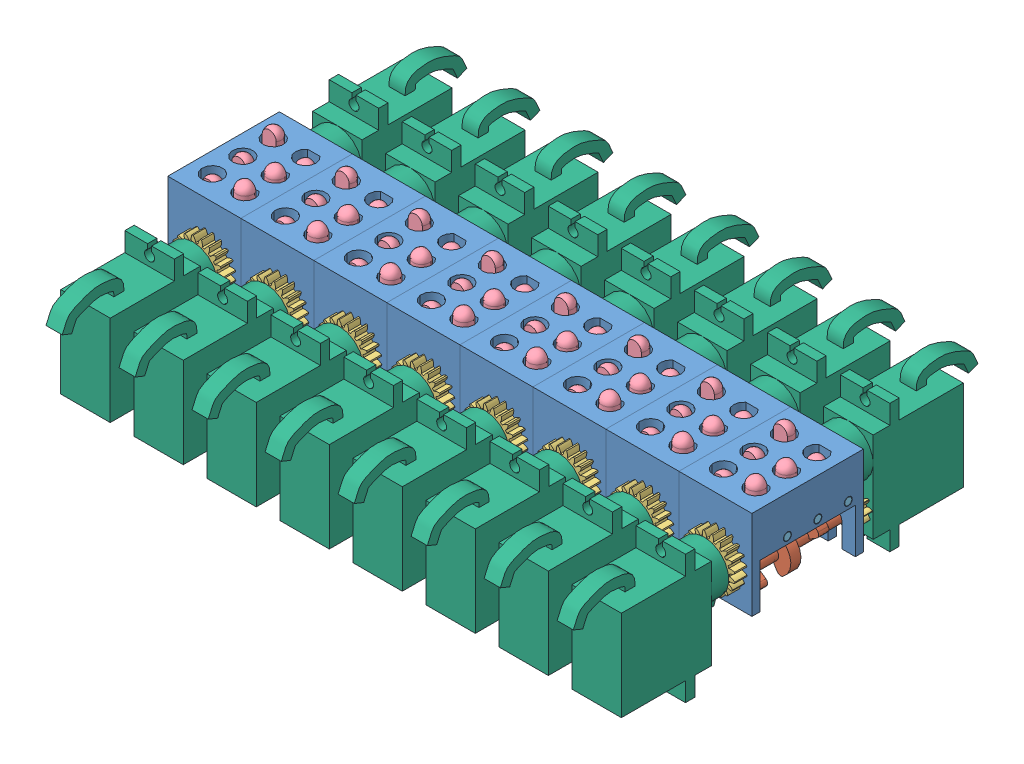
SolidWorks assembly Сборка1, configuration По умолчанию. Lengths in mm.
Overall size (146.18 34.4 106.77).
192 component instances, 6 part files, 21 mates.
Components (placement in the parent):
- cell-1: cell [По умолчанию] at origin size (20.18 34.4 106.77)
  - housing-1: housing [По умолчанию] at origin size (18 22 27.5)
  - rotor-1: rotor [По умолчанию] at (4 -16 -17.35) x (0.358478 -0.933538 0) z (0 0 1) size (9 8.9 33.5)
    - rotor-1: rotor [По умолчанию] at origin size (9 8.9 33.5)
    - spur gear_am-1: spur gear_am [Metric - Spur gear 0.6M 10T 20PA 3FW ---S10N75H50L3N] at (0 0 3) x (0 0 -1) z (1 0 0) size (3 6.89 7.2)
  - pin-2: pin [По умолчанию] at (4 -9.7016 -0.75) x (-1 0 0) z (0 0 -1) size (4 14 4.5)
  - pin-3: pin [По умолчанию] at (4 -12.4261 -8.25) x (-1 0 0) z (0 0 -1) size (4 14 4.5)
  - separator-1: separator [По умолчанию] at (0 -9.3 5) size (9 1.75 1.75)
  - separator-2: separator [По умолчанию] at (0 -9.3 -2.5) size (9 1.75 1.75)
  - rotor-3: rotor [По умолчанию] at (-4 -16 18.952) x (0.331867 0.943326 0) z (0 0 -1) size (9 8.9 33.5)
    - rotor-1: rotor [По умолчанию] at origin size (9 8.9 33.5)
    - spur gear_am-1: spur gear_am [Metric - Spur gear 0.6M 10T 20PA 3FW ---S10N75H50L3N] at (0 0 3) x (0 0 -1) z (1 0 0) size (3 6.89 7.2)
  - pin-4: pin [По умолчанию] at (4 -9.3768 6.75) x (-1 0 0) z (0 0 -1) size (4 14 4.5)
  - separator-3: separator [По умолчанию] at (0 -9.3 -10) size (9 1.75 1.75)
  - servo-1: servo [По умолчанию] at (-3.6042 -4.7 -44.85) x (-1 0 0) z (0 1 0) size (12.2 36.83 31.7)
  - servo-2: servo [По умолчанию] at (3.4181 -4.7 46.452) x (1 0 0) z (0 1 0) size (12.2 36.83 31.7)
  - spur gear_am-1: spur gear_am [Metric - Spur gear 0.6M 20T 20PA 3FW ---S20N75H50L5N] at (3.4181 -10.8 15.952) x (0 0 1) z (-0.999929 -0.011884 0) size (3 13.08 13.08)
  - spur gear_am-2: spur gear_am [Metric - Spur gear 0.6M 20T 20PA 3FW ---S20N75H50L5N] at (-3.6042 -10.8 -14.35) x (0 0 -1) z (1 0 0) size (3 13.08 13.08)
  - separator-4: separator [По умолчанию] at (-9 -9.3 -5) size (9 1.75 1.75)
  - separator-5: separator [По умолчанию] at (-9 -9.3 2.5) size (9 1.75 1.75)
  - separator-6: separator [По умолчанию] at (-9 -9.3 10) size (9 1.75 1.75)
  - pin-5: pin [По умолчанию] at (-4 -9.2986 -6.25) size (4 14 4.5)
  - pin-6: pin [По умолчанию] at (-4 -11.4111 1.25) size (4 14 4.5)
  - pin-7: pin [По умолчанию] at (-4 -12.4437 8.75) size (4 14 4.5)
- cell-2: cell [По умолчанию] at (18 0 0) size (20.18 34.4 106.77)
  - housing-1: housing [По умолчанию] at origin size (18 22 27.5)
  - rotor-1: rotor [По умолчанию] at (4 -16 -17.35) x (0.358478 -0.933538 0) z (0 0 1) size (9 8.9 33.5)
    - rotor-1: rotor [По умолчанию] at origin size (9 8.9 33.5)
    - spur gear_am-1: spur gear_am [Metric - Spur gear 0.6M 10T 20PA 3FW ---S10N75H50L3N] at (0 0 3) x (0 0 -1) z (1 0 0) size (3 6.89 7.2)
  - pin-2: pin [По умолчанию] at (4 -9.7016 -0.75) x (-1 0 0) z (0 0 -1) size (4 14 4.5)
  - pin-3: pin [По умолчанию] at (4 -12.4261 -8.25) x (-1 0 0) z (0 0 -1) size (4 14 4.5)
  - separator-1: separator [По умолчанию] at (0 -9.3 5) size (9 1.75 1.75)
  - separator-2: separator [По умолчанию] at (0 -9.3 -2.5) size (9 1.75 1.75)
  - rotor-3: rotor [По умолчанию] at (-4 -16 18.952) x (0.331867 0.943326 0) z (0 0 -1) size (9 8.9 33.5)
    - rotor-1: rotor [По умолчанию] at origin size (9 8.9 33.5)
    - spur gear_am-1: spur gear_am [Metric - Spur gear 0.6M 10T 20PA 3FW ---S10N75H50L3N] at (0 0 3) x (0 0 -1) z (1 0 0) size (3 6.89 7.2)
  - pin-4: pin [По умолчанию] at (4 -9.3768 6.75) x (-1 0 0) z (0 0 -1) size (4 14 4.5)
  - separator-3: separator [По умолчанию] at (0 -9.3 -10) size (9 1.75 1.75)
  - servo-1: servo [По умолчанию] at (-3.6042 -4.7 -44.85) x (-1 0 0) z (0 1 0) size (12.2 36.83 31.7)
  - servo-2: servo [По умолчанию] at (3.4181 -4.7 46.452) x (1 0 0) z (0 1 0) size (12.2 36.83 31.7)
  - spur gear_am-1: spur gear_am [Metric - Spur gear 0.6M 20T 20PA 3FW ---S20N75H50L5N] at (3.4181 -10.8 15.952) x (0 0 1) z (-0.999929 -0.011884 0) size (3 13.08 13.08)
  - spur gear_am-2: spur gear_am [Metric - Spur gear 0.6M 20T 20PA 3FW ---S20N75H50L5N] at (-3.6042 -10.8 -14.35) x (0 0 -1) z (1 0 0) size (3 13.08 13.08)
  - separator-4: separator [По умолчанию] at (-9 -9.3 -5) size (9 1.75 1.75)
  - separator-5: separator [По умолчанию] at (-9 -9.3 2.5) size (9 1.75 1.75)
  - separator-6: separator [По умолчанию] at (-9 -9.3 10) size (9 1.75 1.75)
  - pin-5: pin [По умолчанию] at (-4 -9.2986 -6.25) size (4 14 4.5)
  - pin-6: pin [По умолчанию] at (-4 -11.4111 1.25) size (4 14 4.5)
  - pin-7: pin [По умолчанию] at (-4 -12.4437 8.75) size (4 14 4.5)
- cell-3: cell [По умолчанию] at (36 0 0) size (20.18 34.4 106.77)
  - housing-1: housing [По умолчанию] at origin size (18 22 27.5)
  - rotor-1: rotor [По умолчанию] at (4 -16 -17.35) x (0.358478 -0.933538 0) z (0 0 1) size (9 8.9 33.5)
    - rotor-1: rotor [По умолчанию] at origin size (9 8.9 33.5)
    - spur gear_am-1: spur gear_am [Metric - Spur gear 0.6M 10T 20PA 3FW ---S10N75H50L3N] at (0 0 3) x (0 0 -1) z (1 0 0) size (3 6.89 7.2)
  - pin-2: pin [По умолчанию] at (4 -9.7016 -0.75) x (-1 0 0) z (0 0 -1) size (4 14 4.5)
  - pin-3: pin [По умолчанию] at (4 -12.4261 -8.25) x (-1 0 0) z (0 0 -1) size (4 14 4.5)
  - separator-1: separator [По умолчанию] at (0 -9.3 5) size (9 1.75 1.75)
  - separator-2: separator [По умолчанию] at (0 -9.3 -2.5) size (9 1.75 1.75)
  - rotor-3: rotor [По умолчанию] at (-4 -16 18.952) x (0.331867 0.943326 0) z (0 0 -1) size (9 8.9 33.5)
    - rotor-1: rotor [По умолчанию] at origin size (9 8.9 33.5)
    - spur gear_am-1: spur gear_am [Metric - Spur gear 0.6M 10T 20PA 3FW ---S10N75H50L3N] at (0 0 3) x (0 0 -1) z (1 0 0) size (3 6.89 7.2)
  - pin-4: pin [По умолчанию] at (4 -9.3768 6.75) x (-1 0 0) z (0 0 -1) size (4 14 4.5)
  - separator-3: separator [По умолчанию] at (0 -9.3 -10) size (9 1.75 1.75)
  - servo-1: servo [По умолчанию] at (-3.6042 -4.7 -44.85) x (-1 0 0) z (0 1 0) size (12.2 36.83 31.7)
  - servo-2: servo [По умолчанию] at (3.4181 -4.7 46.452) x (1 0 0) z (0 1 0) size (12.2 36.83 31.7)
  - spur gear_am-1: spur gear_am [Metric - Spur gear 0.6M 20T 20PA 3FW ---S20N75H50L5N] at (3.4181 -10.8 15.952) x (0 0 1) z (-0.999929 -0.011884 0) size (3 13.08 13.08)
  - spur gear_am-2: spur gear_am [Metric - Spur gear 0.6M 20T 20PA 3FW ---S20N75H50L5N] at (-3.6042 -10.8 -14.35) x (0 0 -1) z (1 0 0) size (3 13.08 13.08)
  - separator-4: separator [По умолчанию] at (-9 -9.3 -5) size (9 1.75 1.75)
  - separator-5: separator [По умолчанию] at (-9 -9.3 2.5) size (9 1.75 1.75)
  - separator-6: separator [По умолчанию] at (-9 -9.3 10) size (9 1.75 1.75)
  - pin-5: pin [По умолчанию] at (-4 -9.2986 -6.25) size (4 14 4.5)
  - pin-6: pin [По умолчанию] at (-4 -11.4111 1.25) size (4 14 4.5)
  - pin-7: pin [По умолчанию] at (-4 -12.4437 8.75) size (4 14 4.5)
- cell-4: cell [По умолчанию] at (54 0 0) size (20.18 34.4 106.77)
  - housing-1: housing [По умолчанию] at origin size (18 22 27.5)
  - rotor-1: rotor [По умолчанию] at (4 -16 -17.35) x (0.358478 -0.933538 0) z (0 0 1) size (9 8.9 33.5)
    - rotor-1: rotor [По умолчанию] at origin size (9 8.9 33.5)
    - spur gear_am-1: spur gear_am [Metric - Spur gear 0.6M 10T 20PA 3FW ---S10N75H50L3N] at (0 0 3) x (0 0 -1) z (1 0 0) size (3 6.89 7.2)
  - pin-2: pin [По умолчанию] at (4 -9.7016 -0.75) x (-1 0 0) z (0 0 -1) size (4 14 4.5)
  - pin-3: pin [По умолчанию] at (4 -12.4261 -8.25) x (-1 0 0) z (0 0 -1) size (4 14 4.5)
  - separator-1: separator [По умолчанию] at (0 -9.3 5) size (9 1.75 1.75)
  - separator-2: separator [По умолчанию] at (0 -9.3 -2.5) size (9 1.75 1.75)
  - rotor-3: rotor [По умолчанию] at (-4 -16 18.952) x (0.331867 0.943326 0) z (0 0 -1) size (9 8.9 33.5)
    - rotor-1: rotor [По умолчанию] at origin size (9 8.9 33.5)
    - spur gear_am-1: spur gear_am [Metric - Spur gear 0.6M 10T 20PA 3FW ---S10N75H50L3N] at (0 0 3) x (0 0 -1) z (1 0 0) size (3 6.89 7.2)
  - pin-4: pin [По умолчанию] at (4 -9.3768 6.75) x (-1 0 0) z (0 0 -1) size (4 14 4.5)
  - separator-3: separator [По умолчанию] at (0 -9.3 -10) size (9 1.75 1.75)
  - servo-1: servo [По умолчанию] at (-3.6042 -4.7 -44.85) x (-1 0 0) z (0 1 0) size (12.2 36.83 31.7)
  - servo-2: servo [По умолчанию] at (3.4181 -4.7 46.452) x (1 0 0) z (0 1 0) size (12.2 36.83 31.7)
  - spur gear_am-1: spur gear_am [Metric - Spur gear 0.6M 20T 20PA 3FW ---S20N75H50L5N] at (3.4181 -10.8 15.952) x (0 0 1) z (-0.999929 -0.011884 0) size (3 13.08 13.08)
  - spur gear_am-2: spur gear_am [Metric - Spur gear 0.6M 20T 20PA 3FW ---S20N75H50L5N] at (-3.6042 -10.8 -14.35) x (0 0 -1) z (1 0 0) size (3 13.08 13.08)
  - separator-4: separator [По умолчанию] at (-9 -9.3 -5) size (9 1.75 1.75)
  - separator-5: separator [По умолчанию] at (-9 -9.3 2.5) size (9 1.75 1.75)
  - separator-6: separator [По умолчанию] at (-9 -9.3 10) size (9 1.75 1.75)
  - pin-5: pin [По умолчанию] at (-4 -9.2986 -6.25) size (4 14 4.5)
  - pin-6: pin [По умолчанию] at (-4 -11.4111 1.25) size (4 14 4.5)
  - pin-7: pin [По умолчанию] at (-4 -12.4437 8.75) size (4 14 4.5)
- cell-5: cell [По умолчанию] at (72 0 0) size (20.18 34.4 106.77)
  - housing-1: housing [По умолчанию] at origin size (18 22 27.5)
  - rotor-1: rotor [По умолчанию] at (4 -16 -17.35) x (0.358478 -0.933538 0) z (0 0 1) size (9 8.9 33.5)
    - rotor-1: rotor [По умолчанию] at origin size (9 8.9 33.5)
    - spur gear_am-1: spur gear_am [Metric - Spur gear 0.6M 10T 20PA 3FW ---S10N75H50L3N] at (0 0 3) x (0 0 -1) z (1 0 0) size (3 6.89 7.2)
  - pin-2: pin [По умолчанию] at (4 -9.7016 -0.75) x (-1 0 0) z (0 0 -1) size (4 14 4.5)
  - pin-3: pin [По умолчанию] at (4 -12.4261 -8.25) x (-1 0 0) z (0 0 -1) size (4 14 4.5)
  - separator-1: separator [По умолчанию] at (0 -9.3 5) size (9 1.75 1.75)
  - separator-2: separator [По умолчанию] at (0 -9.3 -2.5) size (9 1.75 1.75)
  - rotor-3: rotor [По умолчанию] at (-4 -16 18.952) x (0.331867 0.943326 0) z (0 0 -1) size (9 8.9 33.5)
    - rotor-1: rotor [По умолчанию] at origin size (9 8.9 33.5)
    - spur gear_am-1: spur gear_am [Metric - Spur gear 0.6M 10T 20PA 3FW ---S10N75H50L3N] at (0 0 3) x (0 0 -1) z (1 0 0) size (3 6.89 7.2)
  - pin-4: pin [По умолчанию] at (4 -9.3768 6.75) x (-1 0 0) z (0 0 -1) size (4 14 4.5)
  - separator-3: separator [По умолчанию] at (0 -9.3 -10) size (9 1.75 1.75)
  - servo-1: servo [По умолчанию] at (-3.6042 -4.7 -44.85) x (-1 0 0) z (0 1 0) size (12.2 36.83 31.7)
  - servo-2: servo [По умолчанию] at (3.4181 -4.7 46.452) x (1 0 0) z (0 1 0) size (12.2 36.83 31.7)
  - spur gear_am-1: spur gear_am [Metric - Spur gear 0.6M 20T 20PA 3FW ---S20N75H50L5N] at (3.4181 -10.8 15.952) x (0 0 1) z (-0.999929 -0.011884 0) size (3 13.08 13.08)
  - spur gear_am-2: spur gear_am [Metric - Spur gear 0.6M 20T 20PA 3FW ---S20N75H50L5N] at (-3.6042 -10.8 -14.35) x (0 0 -1) z (1 0 0) size (3 13.08 13.08)
  - separator-4: separator [По умолчанию] at (-9 -9.3 -5) size (9 1.75 1.75)
  - separator-5: separator [По умолчанию] at (-9 -9.3 2.5) size (9 1.75 1.75)
  - separator-6: separator [По умолчанию] at (-9 -9.3 10) size (9 1.75 1.75)
  - pin-5: pin [По умолчанию] at (-4 -9.2986 -6.25) size (4 14 4.5)
  - pin-6: pin [По умолчанию] at (-4 -11.4111 1.25) size (4 14 4.5)
  - pin-7: pin [По умолчанию] at (-4 -12.4437 8.75) size (4 14 4.5)
- cell-6: cell [По умолчанию] at (90 0 0) size (20.18 34.4 106.77)
  - housing-1: housing [По умолчанию] at origin size (18 22 27.5)
  - rotor-1: rotor [По умолчанию] at (4 -16 -17.35) x (0.358478 -0.933538 0) z (0 0 1) size (9 8.9 33.5)
    - rotor-1: rotor [По умолчанию] at origin size (9 8.9 33.5)
    - spur gear_am-1: spur gear_am [Metric - Spur gear 0.6M 10T 20PA 3FW ---S10N75H50L3N] at (0 0 3) x (0 0 -1) z (1 0 0) size (3 6.89 7.2)
  - pin-2: pin [По умолчанию] at (4 -9.7016 -0.75) x (-1 0 0) z (0 0 -1) size (4 14 4.5)
  - pin-3: pin [По умолчанию] at (4 -12.4261 -8.25) x (-1 0 0) z (0 0 -1) size (4 14 4.5)
  - separator-1: separator [По умолчанию] at (0 -9.3 5) size (9 1.75 1.75)
  - separator-2: separator [По умолчанию] at (0 -9.3 -2.5) size (9 1.75 1.75)
  - rotor-3: rotor [По умолчанию] at (-4 -16 18.952) x (0.331867 0.943326 0) z (0 0 -1) size (9 8.9 33.5)
    - rotor-1: rotor [По умолчанию] at origin size (9 8.9 33.5)
    - spur gear_am-1: spur gear_am [Metric - Spur gear 0.6M 10T 20PA 3FW ---S10N75H50L3N] at (0 0 3) x (0 0 -1) z (1 0 0) size (3 6.89 7.2)
  - pin-4: pin [По умолчанию] at (4 -9.3768 6.75) x (-1 0 0) z (0 0 -1) size (4 14 4.5)
  - separator-3: separator [По умолчанию] at (0 -9.3 -10) size (9 1.75 1.75)
  - servo-1: servo [По умолчанию] at (-3.6042 -4.7 -44.85) x (-1 0 0) z (0 1 0) size (12.2 36.83 31.7)
  - servo-2: servo [По умолчанию] at (3.4181 -4.7 46.452) x (1 0 0) z (0 1 0) size (12.2 36.83 31.7)
  - spur gear_am-1: spur gear_am [Metric - Spur gear 0.6M 20T 20PA 3FW ---S20N75H50L5N] at (3.4181 -10.8 15.952) x (0 0 1) z (-0.999929 -0.011884 0) size (3 13.08 13.08)
  - spur gear_am-2: spur gear_am [Metric - Spur gear 0.6M 20T 20PA 3FW ---S20N75H50L5N] at (-3.6042 -10.8 -14.35) x (0 0 -1) z (1 0 0) size (3 13.08 13.08)
  - separator-4: separator [По умолчанию] at (-9 -9.3 -5) size (9 1.75 1.75)
  - separator-5: separator [По умолчанию] at (-9 -9.3 2.5) size (9 1.75 1.75)
  - separator-6: separator [По умолчанию] at (-9 -9.3 10) size (9 1.75 1.75)
  - pin-5: pin [По умолчанию] at (-4 -9.2986 -6.25) size (4 14 4.5)
  - pin-6: pin [По умолчанию] at (-4 -11.4111 1.25) size (4 14 4.5)
  - pin-7: pin [По умолчанию] at (-4 -12.4437 8.75) size (4 14 4.5)
- cell-7: cell [По умолчанию] at (108 0 0) size (20.18 34.4 106.77)
  - housing-1: housing [По умолчанию] at origin size (18 22 27.5)
  - rotor-1: rotor [По умолчанию] at (4 -16 -17.35) x (0.358478 -0.933538 0) z (0 0 1) size (9 8.9 33.5)
    - rotor-1: rotor [По умолчанию] at origin size (9 8.9 33.5)
    - spur gear_am-1: spur gear_am [Metric - Spur gear 0.6M 10T 20PA 3FW ---S10N75H50L3N] at (0 0 3) x (0 0 -1) z (1 0 0) size (3 6.89 7.2)
  - pin-2: pin [По умолчанию] at (4 -9.7016 -0.75) x (-1 0 0) z (0 0 -1) size (4 14 4.5)
  - pin-3: pin [По умолчанию] at (4 -12.4261 -8.25) x (-1 0 0) z (0 0 -1) size (4 14 4.5)
  - separator-1: separator [По умолчанию] at (0 -9.3 5) size (9 1.75 1.75)
  - separator-2: separator [По умолчанию] at (0 -9.3 -2.5) size (9 1.75 1.75)
  - rotor-3: rotor [По умолчанию] at (-4 -16 18.952) x (0.331867 0.943326 0) z (0 0 -1) size (9 8.9 33.5)
    - rotor-1: rotor [По умолчанию] at origin size (9 8.9 33.5)
    - spur gear_am-1: spur gear_am [Metric - Spur gear 0.6M 10T 20PA 3FW ---S10N75H50L3N] at (0 0 3) x (0 0 -1) z (1 0 0) size (3 6.89 7.2)
  - pin-4: pin [По умолчанию] at (4 -9.3768 6.75) x (-1 0 0) z (0 0 -1) size (4 14 4.5)
  - separator-3: separator [По умолчанию] at (0 -9.3 -10) size (9 1.75 1.75)
  - servo-1: servo [По умолчанию] at (-3.6042 -4.7 -44.85) x (-1 0 0) z (0 1 0) size (12.2 36.83 31.7)
  - servo-2: servo [По умолчанию] at (3.4181 -4.7 46.452) x (1 0 0) z (0 1 0) size (12.2 36.83 31.7)
  - spur gear_am-1: spur gear_am [Metric - Spur gear 0.6M 20T 20PA 3FW ---S20N75H50L5N] at (3.4181 -10.8 15.952) x (0 0 1) z (-0.999929 -0.011884 0) size (3 13.08 13.08)
  - spur gear_am-2: spur gear_am [Metric - Spur gear 0.6M 20T 20PA 3FW ---S20N75H50L5N] at (-3.6042 -10.8 -14.35) x (0 0 -1) z (1 0 0) size (3 13.08 13.08)
  - separator-4: separator [По умолчанию] at (-9 -9.3 -5) size (9 1.75 1.75)
  - separator-5: separator [По умолчанию] at (-9 -9.3 2.5) size (9 1.75 1.75)
  - separator-6: separator [По умолчанию] at (-9 -9.3 10) size (9 1.75 1.75)
  - pin-5: pin [По умолчанию] at (-4 -9.2986 -6.25) size (4 14 4.5)
  - pin-6: pin [По умолчанию] at (-4 -11.4111 1.25) size (4 14 4.5)
  - pin-7: pin [По умолчанию] at (-4 -12.4437 8.75) size (4 14 4.5)
- cell-8: cell [По умолчанию] at (126 0 0) size (20.18 34.4 106.77)
  - housing-1: housing [По умолчанию] at origin size (18 22 27.5)
  - rotor-1: rotor [По умолчанию] at (4 -16 -17.35) x (0.358478 -0.933538 0) z (0 0 1) size (9 8.9 33.5)
    - rotor-1: rotor [По умолчанию] at origin size (9 8.9 33.5)
    - spur gear_am-1: spur gear_am [Metric - Spur gear 0.6M 10T 20PA 3FW ---S10N75H50L3N] at (0 0 3) x (0 0 -1) z (1 0 0) size (3 6.89 7.2)
  - pin-2: pin [По умолчанию] at (4 -9.7016 -0.75) x (-1 0 0) z (0 0 -1) size (4 14 4.5)
  - pin-3: pin [По умолчанию] at (4 -12.4261 -8.25) x (-1 0 0) z (0 0 -1) size (4 14 4.5)
  - separator-1: separator [По умолчанию] at (0 -9.3 5) size (9 1.75 1.75)
  - separator-2: separator [По умолчанию] at (0 -9.3 -2.5) size (9 1.75 1.75)
  - rotor-3: rotor [По умолчанию] at (-4 -16 18.952) x (0.331867 0.943326 0) z (0 0 -1) size (9 8.9 33.5)
    - rotor-1: rotor [По умолчанию] at origin size (9 8.9 33.5)
    - spur gear_am-1: spur gear_am [Metric - Spur gear 0.6M 10T 20PA 3FW ---S10N75H50L3N] at (0 0 3) x (0 0 -1) z (1 0 0) size (3 6.89 7.2)
  - pin-4: pin [По умолчанию] at (4 -9.3768 6.75) x (-1 0 0) z (0 0 -1) size (4 14 4.5)
  - separator-3: separator [По умолчанию] at (0 -9.3 -10) size (9 1.75 1.75)
  - servo-1: servo [По умолчанию] at (-3.6042 -4.7 -44.85) x (-1 0 0) z (0 1 0) size (12.2 36.83 31.7)
  - servo-2: servo [По умолчанию] at (3.4181 -4.7 46.452) x (1 0 0) z (0 1 0) size (12.2 36.83 31.7)
  - spur gear_am-1: spur gear_am [Metric - Spur gear 0.6M 20T 20PA 3FW ---S20N75H50L5N] at (3.4181 -10.8 15.952) x (0 0 1) z (-0.999929 -0.011884 0) size (3 13.08 13.08)
  - spur gear_am-2: spur gear_am [Metric - Spur gear 0.6M 20T 20PA 3FW ---S20N75H50L5N] at (-3.6042 -10.8 -14.35) x (0 0 -1) z (1 0 0) size (3 13.08 13.08)
  - separator-4: separator [По умолчанию] at (-9 -9.3 -5) size (9 1.75 1.75)
  - separator-5: separator [По умолчанию] at (-9 -9.3 2.5) size (9 1.75 1.75)
  - separator-6: separator [По умолчанию] at (-9 -9.3 10) size (9 1.75 1.75)
  - pin-5: pin [По умолчанию] at (-4 -9.2986 -6.25) size (4 14 4.5)
  - pin-6: pin [По умолчанию] at (-4 -11.4111 1.25) size (4 14 4.5)
  - pin-7: pin [По умолчанию] at (-4 -12.4437 8.75) size (4 14 4.5)
Mates (geometry in assembly coordinates):
- Совпадение1: coincident anti-aligned: plane of cell-1/housing-1 through (9 -3.5 -13.75) normal (1 0 0); plane of cell-2/housing-1 through (9 -3.5 -13.75) normal (-1 0 0)
- Совпадение2: coincident aligned: plane of cell-1/housing-1 through (-9 -3.5 13.75) normal (0 0 1); plane of cell-2/housing-1 through (9 -3.5 13.75) normal (0 0 1)
- Совпадение3: coincident aligned: plane of cell-1/housing-1 through (0 0 0) normal (0 1 0); plane of cell-2/housing-1 through (18 0 0) normal (0 1 0)
- Совпадение4: coincident anti-aligned: plane of cell-2/housing-1 through (27 -3.5 -13.75) normal (1 0 0); plane of cell-3/housing-1 through (27 -3.5 -13.75) normal (-1 0 0)
- Совпадение5: coincident aligned: plane of cell-1/housing-1 through (-9 -3.5 13.75) normal (0 0 1); plane of cell-3/housing-1 through (27 -3.5 13.75) normal (0 0 1)
- Совпадение6: coincident aligned: plane of cell-1/housing-1 through (0 0 0) normal (0 1 0); plane of cell-3/housing-1 through (36 0 0) normal (0 1 0)
- Совпадение7: coincident aligned: plane of cell-1/housing-1 through (-9 -3.5 13.75) normal (0 0 1); plane of cell-4/housing-1 through (45 -3.5 13.75) normal (0 0 1)
- Совпадение8: coincident aligned: plane of cell-1/housing-1 through (0 0 0) normal (0 1 0); plane of cell-4/housing-1 through (54 0 0) normal (0 1 0)
- Совпадение9: coincident anti-aligned: plane of cell-3/housing-1 through (45 -3.5 -13.75) normal (1 0 0); plane of cell-4/housing-1 through (45 -3.5 -13.75) normal (-1 0 0)
- Совпадение10: coincident aligned: plane of cell-1/housing-1 through (-9 -3.5 13.75) normal (0 0 1); plane of cell-5/housing-1 through (63 -3.5 13.75) normal (0 0 1)
- Совпадение11: coincident aligned: plane of cell-1/housing-1 through (0 0 0) normal (0 1 0); plane of cell-5/housing-1 through (72 0 0) normal (0 1 0)
- Совпадение12: coincident anti-aligned: plane of cell-4/housing-1 through (63 -3.5 -13.75) normal (1 0 0); plane of cell-5/housing-1 through (63 -3.5 -13.75) normal (-1 0 0)
- Совпадение13: coincident aligned: plane of cell-1/housing-1 through (-9 -3.5 13.75) normal (0 0 1); plane of cell-6/housing-1 through (81 -3.5 13.75) normal (0 0 1)
- Совпадение14: coincident aligned: plane of cell-1/housing-1 through (0 0 0) normal (0 1 0); plane of cell-6/housing-1 through (90 0 0) normal (0 1 0)
- Совпадение15: coincident anti-aligned: plane of cell-5/housing-1 through (81 -3.5 -13.75) normal (1 0 0); plane of cell-6/housing-1 through (81 -3.5 -13.75) normal (-1 0 0)
- Совпадение16: coincident aligned: plane of cell-1/housing-1 through (-9 -3.5 13.75) normal (0 0 1); plane of cell-7/housing-1 through (99 -3.5 13.75) normal (0 0 1)
- Совпадение17: coincident aligned: plane of cell-1/housing-1 through (0 0 0) normal (0 1 0); plane of cell-7/housing-1 through (108 0 0) normal (0 1 0)
- Совпадение18: coincident anti-aligned: plane of cell-6/housing-1 through (99 -3.5 -13.75) normal (1 0 0); plane of cell-7/housing-1 through (99 -3.5 -13.75) normal (-1 0 0)
- Совпадение19: coincident aligned: plane of cell-1/housing-1 through (-9 -3.5 13.75) normal (0 0 1); plane of cell-8/housing-1 through (117 -3.5 13.75) normal (0 0 1)
- Совпадение20: coincident aligned: plane of cell-1/housing-1 through (0 0 0) normal (0 1 0); plane of cell-8/housing-1 through (126 0 0) normal (0 1 0)
- Совпадение21: coincident anti-aligned: plane of cell-7/housing-1 through (117 -3.5 -13.75) normal (1 0 0); plane of cell-8/housing-1 through (117 -3.5 -13.75) normal (-1 0 0)
